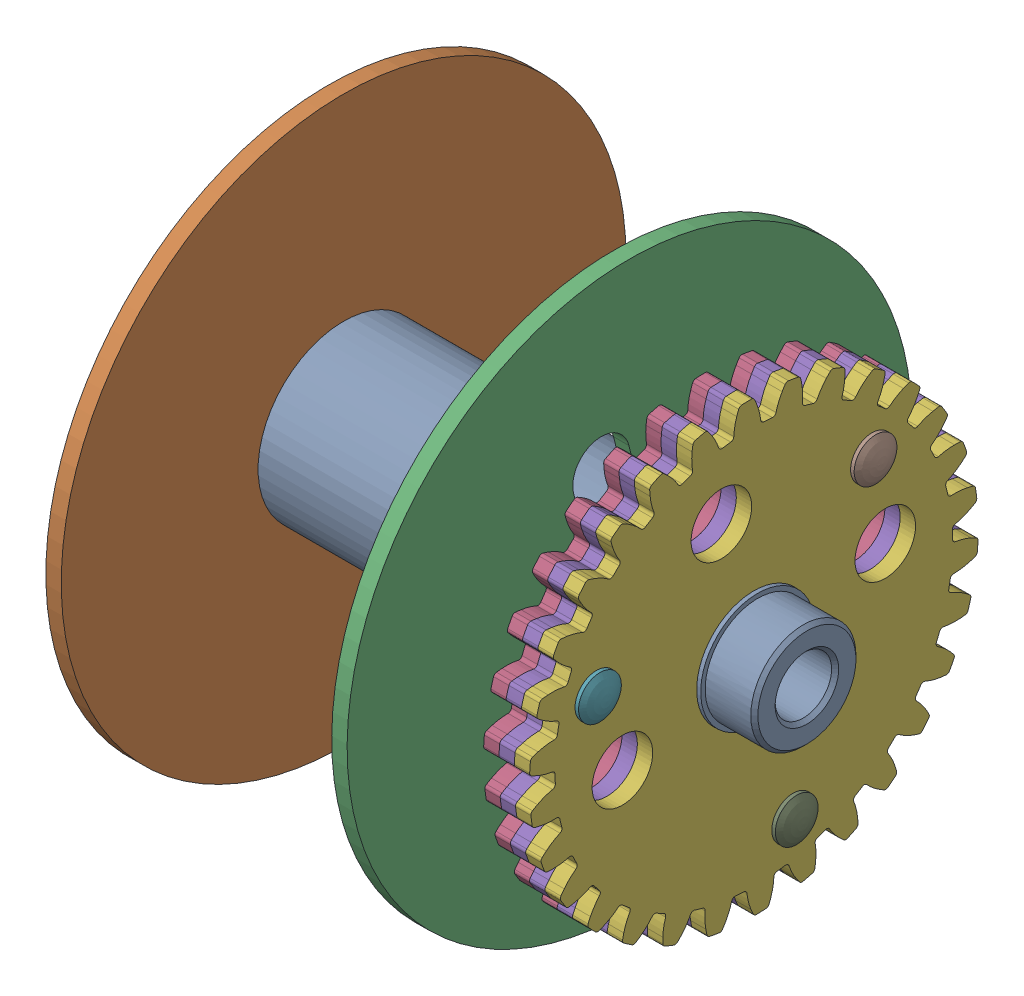
SolidWorks assembly 304432 Reel Assembly, configuration Predeterminado. Lengths in mm.
Overall size (109.98 162.45 162.45).
10 component instances, 5 part files, 0 mates.
Components (placement in the parent):
- 406042 Large Reel Hub-1: 406042 Large Reel Hub [Predeterminado] at origin size (109.98 38.1 38.1)
- 404440 Side Plate-1: 404440 Side Plate [Predeterminado] at (3.3274 0 0) x (0 -0.357166 -0.934041) z (1 0 0) size (125.81 125.81 3.43)
- 404444 Reel Divider-1: 404444 Reel Divider [Predeterminado] at (67.0179 0 0) x (0 0.239819 -0.970818) z (1 0 0) size (125.81 125.81 3.43)
- 304395 Tooth Gear Assembly-1: 304395 Tooth Gear Assembly [Predeterminado] at (87.9094 0 0) x (0 0.960662 -0.277719) z (1 0 0) size (99.67 100.01 13.42)
  - 404443 30T Gear-1: 404443 30T Gear [Predeterminado] at origin size (99.67 100.01 3.42)
  - 404443 30T Gear-2: 404443 30T Gear [Predeterminado] at (0 0 3.4163) size (99.67 100.01 3.42)
  - 404443 30T Gear-3: 404443 30T Gear [Predeterminado] at (0 0 6.8326) size (99.67 100.01 3.42)
  - 206078 Rivit-1: 206078 Rivit [Predeterminado] at (0 36.5125 12.6289) x (0 0 -1) z (-0.029007 -0.999579 0) size (13.42 9.53 9.53)
  - 206078 Rivit-2: 206078 Rivit [Predeterminado] at (31.6208 -18.2563 12.6289) x (0 0 -1) z (0.972835 0.231501 0) size (13.42 9.53 9.53)
  - 206078 Rivit-3: 206078 Rivit [Predeterminado] at (-31.6208 -18.2563 12.6289) x (0 0 -1) z (-0.172822 0.984953 0) size (13.42 9.53 9.53)
